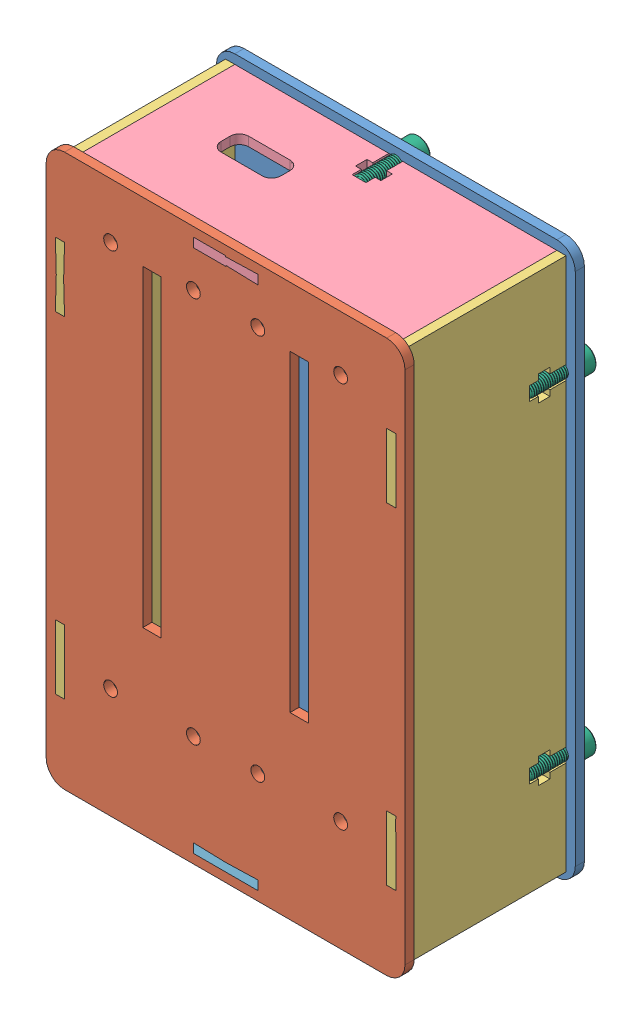
SolidWorks assembly SliderBox, configuration Default. Lengths in mm.
Overall size (78 120.18 42.14).
13 component instances, 7 part files, 27 mates.
Components (placement in the parent):
- SliderBottom-1: SliderBottom [Default] at (-27.6871 57.7085 72.1528) size (78 120 2)
- SliderTop-1: SliderTop [Default] at (-27.6871 57.7085 109.1528) size (78 120 2)
- SlideSide-1: SlideSide [Default] at (-25.6871 175.7085 109.1528) x (0 -1 0) z (1 0 0) size (116 39 2)
- SlideSide-2: SlideSide [Default] at (46.3129 175.7085 109.1528) x (0 -1 0) z (1 0 0) size (116 39 2)
- SlideSideUp-2: SlideSideUp [Default] at (-23.6871 175.7085 74.1528) x (1 0 0) z (0 -1 0) size (70 39 2)
- SlideSideDown-1: SlideSideDown [Default] at (-23.6871 61.7085 74.1528) x (1 0 0) z (0 -1 0) size (70 39 2)
- 92290A115 - ScrewM3L10 -1: 92290A115 - ScrewM3L10  [92290A115] at (-24.6871 153.7085 82.1528) size (5.5 5.5 13.58)
- 92290A115 - ScrewM3L10 -2: 92290A115 - ScrewM3L10  [92290A115] at (11.3129 174.7085 82.1528) size (5.5 5.5 13.58)
- 92290A115 - ScrewM3L10 -3: 92290A115 - ScrewM3L10  [92290A115] at (47.3129 81.7085 82.1528) size (5.5 5.5 13.58)
- 92290A115 - ScrewM3L10 -4: 92290A115 - ScrewM3L10  [92290A115] at (11.3129 60.7085 82.1528) size (5.5 5.5 13.58)
- 92290A115 - ScrewM3L10 -5: 92290A115 - ScrewM3L10  [92290A115] at (47.3129 153.7085 82.1528) size (5.5 5.5 13.58)
- 92290A115 - ScrewM3L10 -6: 92290A115 - ScrewM3L10  [92290A115] at (-24.6871 81.7085 82.1528) size (5.5 5.5 13.58)
- 94150A325 - NutM3-7: 94150A325 - NutM3 [94150A325] at (11.3129 60.7085 78.8528) x (1 0 0) z (0 -1 0) size (5.5 2.58 6.35)
Mates (geometry in assembly coordinates):
- Coincident10: coincident anti-aligned: plane of SliderBottom-1 through (18.3129 175.7085 74.1528) normal (-1 0 0); plane of SlideSideUp-2 through (18.3129 173.7085 74.1528) normal (1 0 0)
- Coincident12: coincident anti-aligned: plane of SliderBottom-1 through (4.3129 175.7085 74.1528) normal (0 -1 0); plane of SlideSideUp-2 through (-23.6871 175.7085 74.1528) normal (0 1 0)
- Coincident16: coincident anti-aligned: plane of SliderBottom-1 through (-27.6871 57.7085 74.1528) normal (0 0 1); plane of SlideSideDown-1 through (18.3129 59.7085 74.1528) normal (0 0 -1)
- Coincident17: coincident anti-aligned: plane of SliderBottom-1 through (18.3129 59.7085 74.1528) normal (-1 0 0); plane of SlideSideDown-1 through (18.3129 59.7085 74.1528) normal (1 0 0)
- Coincident18: coincident anti-aligned: plane of SliderBottom-1 through (4.3129 59.7085 74.1528) normal (0 1 0); plane of SlideSideDown-1 through (-23.6871 59.7085 74.1528) normal (0 -1 0)
- Coincident19: coincident anti-aligned: plane of SliderBottom-1 through (-27.6871 57.7085 74.1528) normal (0 0 1); plane of SlideSideUp-2 through (18.3129 173.7085 74.1528) normal (0 0 -1)
- Coincident20: coincident anti-aligned: plane of SliderBottom-1 through (-27.6871 57.7085 74.1528) normal (0 0 1); plane of SlideSide-1 through (-23.6871 88.7085 74.1528) normal (0 0 -1)
- Coincident21: coincident anti-aligned: plane of SliderBottom-1 through (-23.6871 146.7085 74.1528) normal (-1 0 0); plane of SlideSide-1 through (-23.6871 175.7085 109.1528) normal (1 0 0)
- Coincident22: coincident anti-aligned: plane of SliderBottom-1 through (-25.6871 160.7085 74.1528) normal (0 -1 0); plane of SlideSide-1 through (-23.6871 160.7085 74.1528) normal (0 1 0)
- Coincident23: coincident anti-aligned: plane of SliderBottom-1 through (-27.6871 57.7085 74.1528) normal (0 0 1); plane of SlideSide-2 through (48.3129 88.7085 74.1528) normal (0 0 -1)
- Coincident24: coincident anti-aligned: plane of SliderBottom-1 through (48.3129 88.7085 74.1528) normal (-1 0 0); plane of SlideSide-2 through (48.3129 175.7085 109.1528) normal (1 0 0)
- Coincident25: coincident anti-aligned: plane of SliderBottom-1 through (48.3129 146.7085 74.1528) normal (0 1 0); plane of SlideSide-2 through (48.3129 146.7085 72.1528) normal (0 -1 0)
- Concentric1: concentric anti-aligned: circle of SliderBottom-1; circle of 92290A115 - ScrewM3L10 -2
- Coincident26: coincident anti-aligned: plane of SliderBottom-1 through (-27.6871 57.7085 72.1528) normal (0 0 -1); plane of 92290A115 - ScrewM3L10 -2 through (11.3129 174.7085 72.1528) normal (0 0 1)
- Concentric2: concentric anti-aligned: circle of SliderBottom-1; circle of 92290A115 - ScrewM3L10 -1
- Coincident27: coincident anti-aligned: plane of SliderBottom-1 through (-27.6871 57.7085 72.1528) normal (0 0 -1); plane of 92290A115 - ScrewM3L10 -1 through (-24.6871 153.7085 72.1528) normal (0 0 1)
- Concentric3: concentric anti-aligned: circle of SliderBottom-1; circle of 92290A115 - ScrewM3L10 -3
- Coincident28: coincident anti-aligned: plane of SliderBottom-1 through (-27.6871 57.7085 72.1528) normal (0 0 -1); plane of 92290A115 - ScrewM3L10 -3 through (47.3129 81.7085 72.1528) normal (0 0 1)
- Concentric4: concentric anti-aligned: circle of SliderBottom-1; circle of 92290A115 - ScrewM3L10 -5
- Coincident29: coincident anti-aligned: plane of SliderBottom-1 through (-27.6871 57.7085 72.1528) normal (0 0 -1); plane of 92290A115 - ScrewM3L10 -5 through (47.3129 153.7085 72.1528) normal (0 0 1)
- Concentric5: concentric anti-aligned: circle of SliderBottom-1; circle of 92290A115 - ScrewM3L10 -6
- Coincident30: coincident anti-aligned: plane of SliderBottom-1 through (-27.6871 57.7085 72.1528) normal (0 0 -1); plane of 92290A115 - ScrewM3L10 -6 through (-24.6871 81.7085 72.1528) normal (0 0 1)
- Concentric6: concentric aligned: circle of SliderBottom-1; circle of 92290A115 - ScrewM3L10 -4
- Coincident31: coincident anti-aligned: plane of SliderBottom-1 through (-27.6871 57.7085 72.1528) normal (0 0 -1); plane of 92290A115 - ScrewM3L10 -4 through (11.3129 60.7085 72.1528) normal (0 0 1)
- Parallel1: parallel anti-aligned: plane of SlideSideDown-1 through (14.0629 59.7085 80.1528) normal (-1 0 0); plane of 94150A325 - NutM3-7 through (14.0629 59.1208 80.0528) normal (1 0 0)
- Concentric7: concentric anti-aligned: circle of 92290A115 - ScrewM3L10 -4; circle of 94150A325 - NutM3-7
- Coincident32: coincident anti-aligned: plane of SlideSideDown-1 through (14.0629 59.7085 77.6528) normal (0 0 1); plane of 94150A325 - NutM3-7 through (11.3129 63.8839 77.6528) normal (0 0 -1)
